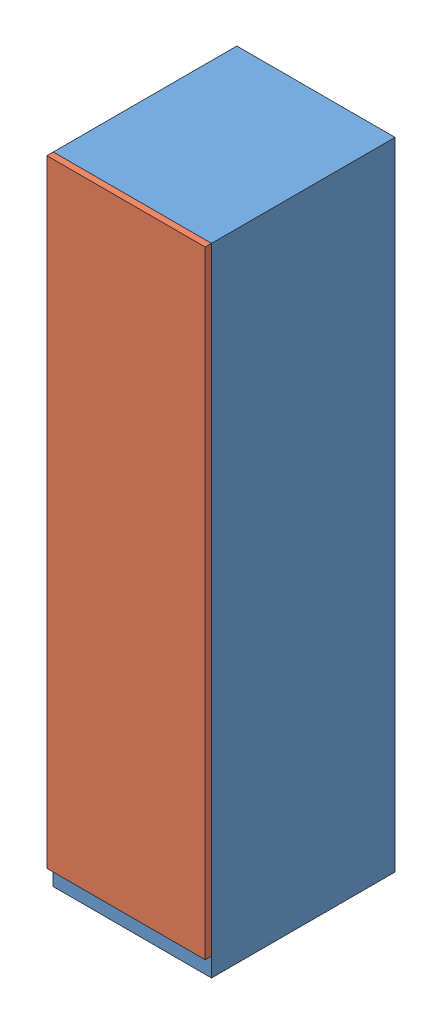
SolidWorks assembly PAX-L, configuration Standard. Lengths in mm.
Overall size (500 2010 600).
7 component instances, 5 part files, 18 mates.
Components (placement in the parent):
- Pax-Korpus-Kleiderschrank-1: Pax-Korpus-Kleiderschrank [Standard] at (-317.8358 -932.7261 1650) size (500 2010 580)
- BALLSTAD-Tür-1: BALLSTAD-Tür [Standard] at (-317.8358 102.2739 1940) size (500 1950 20)
- KOMPLEMENT-Regalbode-1: KOMPLEMENT-Regalbode [Standard] at (-317.8358 -752.7261 1655) size (480 10 570)
- KOMPLIMENT-Schublade-1: KOMPLIMENT-Schublade [Standard] at (-317.8358 -732.7261 1655) size (480 160 570)
- KOMPLEMENT-Regalbode-2: KOMPLEMENT-Regalbode [Standard] at (-317.8358 -562.7261 1655) size (480 10 570)
- KOMPLEMENT-Regalbode-3: KOMPLEMENT-Regalbode [Standard] at (-317.8358 907.2739 1655) size (480 10 570)
- KOMPLEMENT-Kleiderstange-1: KOMPLEMENT-Kleiderstange [Standard] at (-557.8358 692.2739 1660) size (480 50 30)
Mates (geometry in assembly coordinates):
- Deckungsgleich1: coincident anti-aligned: plane of BALLSTAD-Tür-1 through (-317.8358 102.2739 1940) normal (0 0 -1); plane of Pax-Korpus-Kleiderschrank-1 through (-567.8358 -922.7261 1940) normal (0 0 1)
- Deckungsgleich2: coincident aligned: plane of BALLSTAD-Tür-1 through (-567.8358 -872.7261 1960) normal (-1 0 0); plane of Pax-Korpus-Kleiderschrank-1 through (-567.8358 -922.7261 1940) normal (-1 0 0)
- Deckungsgleich3: coincident aligned: plane of BALLSTAD-Tür-1 through (-567.8358 1077.2739 1960) normal (0 1 0); plane of Pax-Korpus-Kleiderschrank-1 through (-317.8358 1077.2739 1650) normal (0 1 0)
- Deckungsgleich4: coincident anti-aligned: plane of Pax-Korpus-Kleiderschrank-1 through (-557.8358 1067.2739 1370) normal (0 0 1); plane of KOMPLEMENT-Regalbode-1 through (-557.8358 -742.7261 1370) normal (0 0 -1)
- Deckungsgleich5: coincident: plane of Pax-Korpus-Kleiderschrank-1 through (-557.8358 1067.2739 1940) normal (1 0 0); plane of KOMPLEMENT-Regalbode-1 through (-557.8358 -742.7261 1940) normal (-1 0 0)
- Abstand1: distance = 120 mm anti-aligned: plane of KOMPLEMENT-Regalbode-1 through (-317.8358 -752.7261 1655) normal (0 -1 0); plane of Pax-Korpus-Kleiderschrank-1 through (-317.8358 -872.7261 1650) normal (0 1 0)
- Deckungsgleich7: coincident anti-aligned: plane of Pax-Korpus-Kleiderschrank-1 through (-557.8358 1067.2739 1370) normal (0 0 1); plane of KOMPLIMENT-Schublade-1 through (-557.8358 -722.7261 1370) normal (0 0 -1)
- Deckungsgleich8: coincident: plane of Pax-Korpus-Kleiderschrank-1 through (-557.8358 1067.2739 1940) normal (1 0 0); plane of KOMPLIMENT-Schublade-1 through (-557.8358 -722.7261 1940) normal (-1 0 0)
- Abstand2: distance = 10 mm: plane of KOMPLEMENT-Regalbode-1 through (-317.8358 -742.7261 1655) normal (0 1 0); plane of KOMPLIMENT-Schublade-1 through (-317.8358 -732.7261 1655) normal (0 -1 0)
- Deckungsgleich10: coincident anti-aligned: plane of Pax-Korpus-Kleiderschrank-1 through (-557.8358 1067.2739 1940) normal (1 0 0); plane of KOMPLEMENT-Regalbode-2 through (-557.8358 -552.7261 1940) normal (-1 0 0)
- Deckungsgleich11: coincident anti-aligned: plane of Pax-Korpus-Kleiderschrank-1 through (-557.8358 1067.2739 1370) normal (0 0 1); plane of KOMPLEMENT-Regalbode-2 through (-557.8358 -552.7261 1370) normal (0 0 -1)
- Abstand3: distance = 10 mm anti-aligned: plane of KOMPLIMENT-Schublade-1 through (-317.8358 -572.7261 1655) normal (0 1 0); plane of KOMPLEMENT-Regalbode-2 through (-317.8358 -562.7261 1655) normal (0 -1 0)
- Deckungsgleich13: coincident anti-aligned: plane of Pax-Korpus-Kleiderschrank-1 through (-557.8358 1067.2739 1940) normal (1 0 0); plane of KOMPLEMENT-Regalbode-3 through (-557.8358 917.2739 1940) normal (-1 0 0)
- Deckungsgleich14: coincident anti-aligned: plane of Pax-Korpus-Kleiderschrank-1 through (-557.8358 1067.2739 1370) normal (0 0 1); plane of KOMPLEMENT-Regalbode-3 through (-557.8358 917.2739 1370) normal (0 0 -1)
- Abstand4: distance = 150 mm anti-aligned: plane of KOMPLEMENT-Regalbode-3 through (-317.8358 917.2739 1655) normal (0 1 0); plane of Pax-Korpus-Kleiderschrank-1 through (-317.8358 1067.2739 1650) normal (0 -1 0)
- Deckungsgleich16: coincident anti-aligned: plane of Pax-Korpus-Kleiderschrank-1 through (-557.8358 1067.2739 1940) normal (1 0 0); plane of KOMPLEMENT-Kleiderstange-1 through (-557.8358 692.2739 1660) normal (-1 0 0)
- Abstand5: distance = 275 mm anti-aligned: plane of KOMPLEMENT-Kleiderstange-1 through (-537.8358 657.2739 1645) normal (0 0 -1); plane of Pax-Korpus-Kleiderschrank-1 through (-557.8358 1067.2739 1370) normal (0 0 1)
- Abstand6: distance = 200 mm: plane of KOMPLEMENT-Kleiderstange-1 through (-537.8358 707.2739 1645) normal (0 1 0); plane of KOMPLEMENT-Regalbode-3 through (-317.8358 907.2739 1655) normal (0 -1 0)
